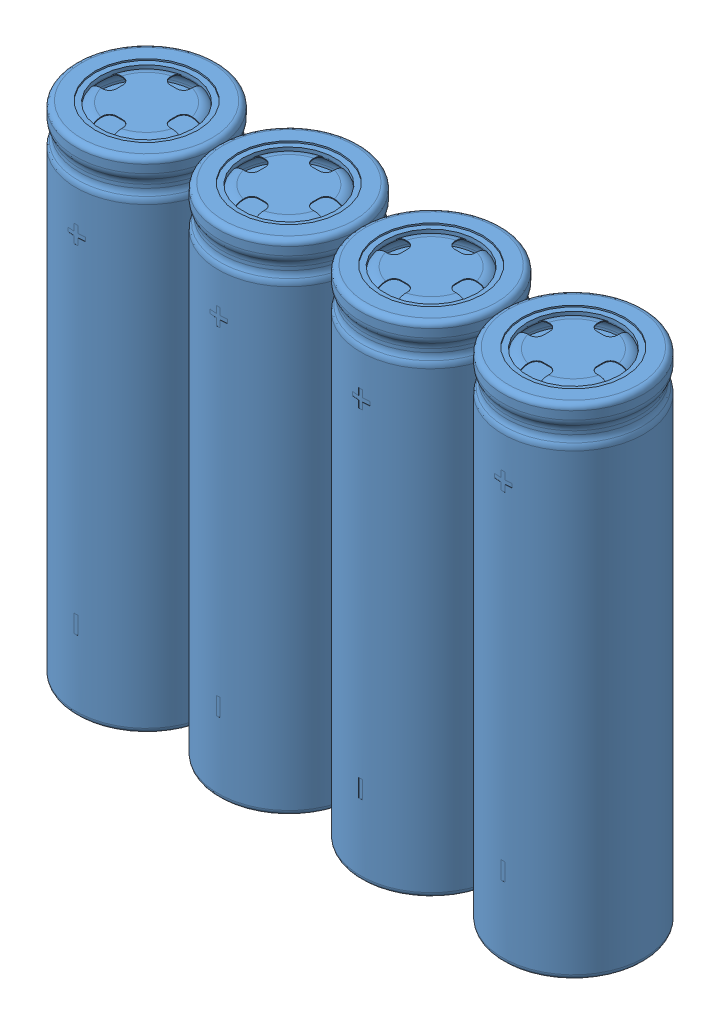
SolidWorks assembly 4P, configuration Default. Lengths in mm.
Overall size (77.72 67.82 21.59).
6 component instances, 3 part files, 0 mates.
Components (placement in the parent):
- 18650-1: 18650 [Default] at (-78.195 13.3753 28.1275) size (18.39 65.05 18.39)
- 18650-2: 18650 [Default] at (-59.653 13.3753 28.1275) size (18.39 65.05 18.39)
- 18650-3: 18650 [Default] at (-41.111 13.3753 28.1275) size (18.39 65.05 18.39)
- 18650-4: 18650 [Default] at (-22.569 13.3753 28.1275) size (18.39 65.05 18.39)
- 4P_TRAY-1: 4P_TRAY [Default] at (-78.195 45.7003 28.1275) x (-1 0 0) z (0 1 0) (suppressed, hidden)
- New4P_TRAY-2: New4P_TRAY [Default] at (-22.569 45.7003 28.3815) x (1 0 0) z (0 1 0) size (77.72 21.59 67.82)
